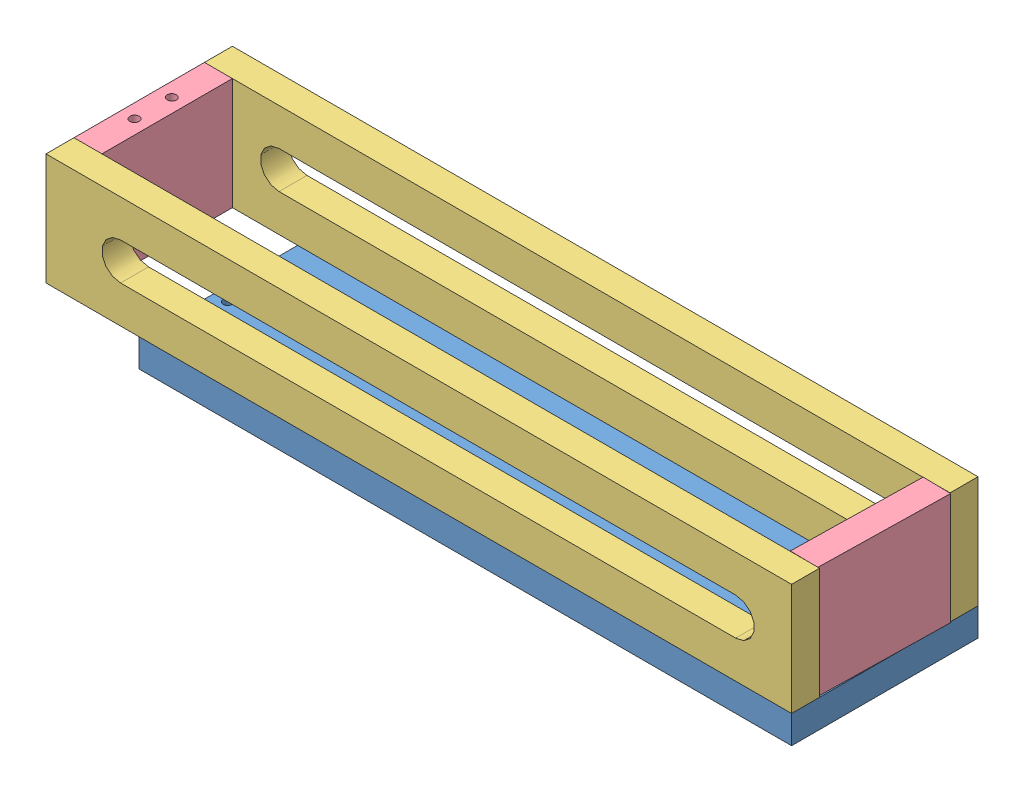
SolidWorks assembly BASE PLATE SUB ASSEMBLY, configuration Default. Lengths in mm.
Overall size (508.61 95.25 127).
14 component instances, 4 part files, 22 mates.
Components (placement in the parent):
- BOTTOM PLATE TERM PROJECT-1: BOTTOM PLATE TERM PROJECT [Default] at origin size (444.5 19.05 127)
- Wooden Dowel Pins-1: Wooden Dowel Pins [97195A416] at (146.05 22.9513 -53.975) x (-0.999911 0 0.013357) z (0 -1 0) size (6.35 6.34 38.1)
- Wooden Dowel Pins-2: Wooden Dowel Pins [97195A416] at (69.85 22.9765 53.975) x (0.629913 0 -0.776666) z (0 1 0) size (6.35 6.34 38.1)
- Wooden Dowel Pins-3: Wooden Dowel Pins [97195A416] at (-44.45 20.3447 -53.975) x (-0.498231 0 0.867044) z (0 -1 0) size (6.35 6.34 38.1)
- Wooden Dowel Pins-4: Wooden Dowel Pins [97195A416] at (-146.05 21.9176 53.975) x (0.282129 0 0.959376) z (0 -1 0) size (6.35 6.34 38.1)
- Wooden Dowel Pins-5: Wooden Dowel Pins [97195A416] at (-44.45 20.5897 53.975) x (-0.986577 0 0.163298) z (0 1 0) size (6.35 6.34 38.1)
- Wooden Dowel Pins-6: Wooden Dowel Pins [97195A416] at (146.05 22.1156 53.975) x (-0.313442 0 -0.949607) z (0 -1 0) size (6.35 6.34 38.1)
- Wooden Dowel Pins-7: Wooden Dowel Pins [97195A416] at (-146.05 21.3061 -53.975) x (-0.996623 0 0.082111) z (0 -1 0) size (6.35 6.34 38.1)
- Wooden Dowel Pins-8: Wooden Dowel Pins [97195A416] at (72.0999 20.5705 -51.7347) x (-0.760649 0 -0.649164) z (0 -1 0) size (6.35 6.34 38.1)
- LATERAL PLATE TERM PROJECT-1: LATERAL PLATE TERM PROJECT [Default] at (-31.75 57.15 44.45) x (1 0 0) z (0 -1 0) size (508 19.05 76.2)
- LATERAL PLATE TERM PROJECT-2: LATERAL PLATE TERM PROJECT [Default] at (-31.75 57.15 -63.5) x (1 0 0) z (0 -1 0) size (508 19.05 76.2)
- FRONT PLATE TERM PROJECT-1: FRONT PLATE TERM PROJECT [Default] at (202.959 57.15 -0.1844) x (0.019112 0 -0.999817) z (0 -1 0) size (88.9 19.05 76.2)
- Wooden Dowel Pins-10: Wooden Dowel Pins [97195A416] at (212.725 20.0463 12.7) x (-0.035971 0 0.999353) z (0 1 0) size (6.35 6.34 38.1)
- FRONT PLATE TERM PROJECT-2: FRONT PLATE TERM PROJECT [Default] at (-266.7 57.15 0) x (0 0 -1) z (0 1 0) size (88.9 19.05 76.2)
Mates (geometry in assembly coordinates):
- Concentric1: concentric aligned: circle of BOTTOM PLATE TERM PROJECT-1; circle of Wooden Dowel Pins-1
- Concentric2: concentric anti-aligned: circle of BOTTOM PLATE TERM PROJECT-1; circle of Wooden Dowel Pins-6
- Concentric3: concentric aligned: circle of BOTTOM PLATE TERM PROJECT-1; circle of Wooden Dowel Pins-5
- Concentric5: concentric aligned: line of BOTTOM PLATE TERM PROJECT-1; line of Wooden Dowel Pins-8 through (69.85 38.8205 -53.975) axis (0 -1 0)
- Concentric6: concentric anti-aligned: axis of BOTTOM PLATE TERM PROJECT-1 through (-44.45 6.35 -53.975) axis (0 1 0); circle of Wooden Dowel Pins-3
- Concentric7: concentric anti-aligned: circle of BOTTOM PLATE TERM PROJECT-1; circle of Wooden Dowel Pins-4
- Concentric8: concentric aligned: circle of BOTTOM PLATE TERM PROJECT-1; circle of Wooden Dowel Pins-7
- Concentric9: concentric aligned: circle of BOTTOM PLATE TERM PROJECT-1; circle of Wooden Dowel Pins-2
- Concentric10: concentric aligned: circle of Wooden Dowel Pins-6; circle of LATERAL PLATE TERM PROJECT-1
- Concentric11: concentric anti-aligned: circle of Wooden Dowel Pins-2; circle of LATERAL PLATE TERM PROJECT-1
- Concentric12: concentric anti-aligned: circle of Wooden Dowel Pins-5; circle of LATERAL PLATE TERM PROJECT-1
- Concentric13: concentric aligned: circle of Wooden Dowel Pins-4; circle of LATERAL PLATE TERM PROJECT-1
- Coincident3: coincident anti-aligned: plane of BOTTOM PLATE TERM PROJECT-1 through (0 19.05 0) normal (0 1 0); plane of LATERAL PLATE TERM PROJECT-1 through (-285.75 19.05 63.5) normal (0 -1 0)
- Concentric14: concentric aligned: circle of Wooden Dowel Pins-7; circle of LATERAL PLATE TERM PROJECT-2
- Concentric15: concentric aligned: circle of Wooden Dowel Pins-3; circle of LATERAL PLATE TERM PROJECT-2
- Coincident5: coincident anti-aligned: plane of BOTTOM PLATE TERM PROJECT-1 through (0 19.05 0) normal (0 1 0); plane of LATERAL PLATE TERM PROJECT-2 through (-285.75 19.05 -44.45) normal (0 -1 0)
- Concentric17: concentric: circle of BOTTOM PLATE TERM PROJECT-1; circle of Wooden Dowel Pins-10
- Coincident9: coincident anti-aligned: plane of BOTTOM PLATE TERM PROJECT-1 through (0 19.05 0) normal (0 1 0); plane of FRONT PLATE TERM PROJECT-1 through (221.156 19.05 44.6216) normal (0 -1 0)
- Coincident10: coincident anti-aligned: plane of LATERAL PLATE TERM PROJECT-1 through (-31.75 57.15 44.45) normal (0 0 -1); plane of FRONT PLATE TERM PROJECT-2 through (-285.75 19.05 44.45) normal (0 0 1)
- Coincident11: coincident anti-aligned: plane of LATERAL PLATE TERM PROJECT-2 through (-31.75 57.15 -44.45) normal (0 0 1); plane of FRONT PLATE TERM PROJECT-2 through (-285.75 19.05 -44.45) normal (0 0 -1)
- Coincident12: coincident anti-aligned: line of LATERAL PLATE TERM PROJECT-1 through (-285.75 95.25 44.45) axis (0 -1 0); line of FRONT PLATE TERM PROJECT-2 through (-285.75 19.05 44.45) axis (0 1 0)
- Coincident13: coincident anti-aligned: line of LATERAL PLATE TERM PROJECT-1 through (-285.75 19.05 63.5) axis (0 0 -1); line of FRONT PLATE TERM PROJECT-2 through (-285.75 19.05 -44.45) axis (0 0 1)
